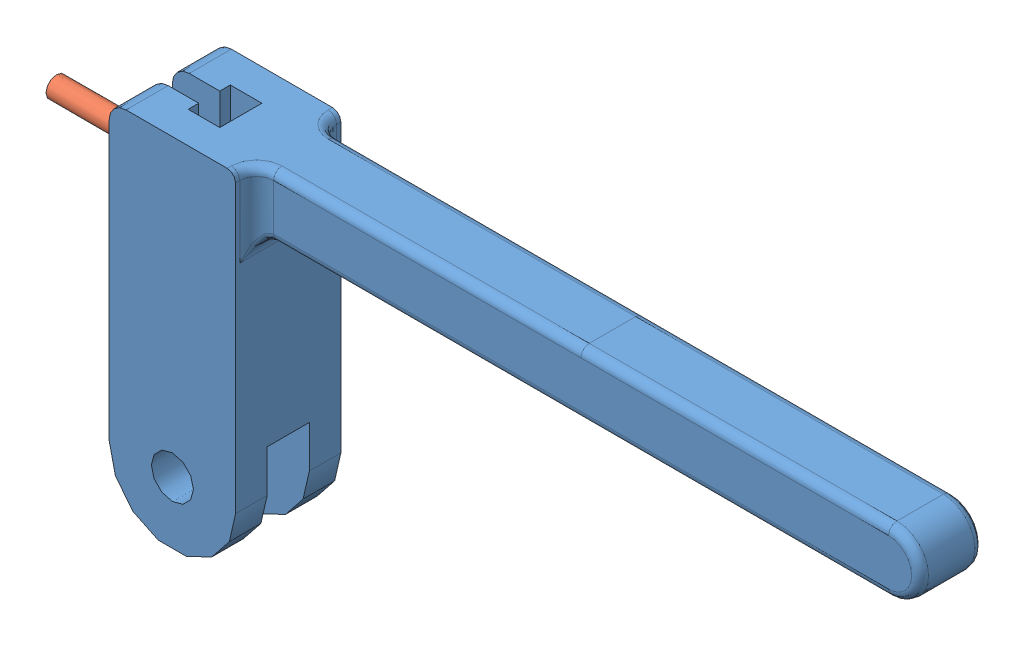
SolidWorks assembly Brake Lever Assembly 1-4, configuration Default. Lengths in mm.
Overall size (134.94 53.98 15.88).
2 component instances, 2 part files, 2 mates.
Components (placement in the parent):
- Brake Lever 1-4-1: Brake Lever 1-4 [Default] at origin size (119.06 53.98 15.88)
- Brake Cable Anchor & Cable 1-4-1: Brake Cable Anchor & Cable 1-4 [Default] at (0 34.29 0) size (27.78 4.76 6.35)
Mates (geometry in assembly coordinates):
- Concentric1: concentric anti-aligned: cylinder of Brake Lever 1-4-1 through (0 34.29 -3.175) axis (0 0 1) radius 2.3813; cylinder of Brake Cable Anchor & Cable 1-4-1 through (0 34.29 3.175) axis (0 0 -1) radius 2.3813
- Concentric2: concentric anti-aligned: cylinder of Brake Lever 1-4-1 through (0 34.29 0) axis (-1 0 0) radius 1.5875; cylinder of Brake Cable Anchor & Cable 1-4-1 through (-25.4 34.29 0) axis (1 0 0) radius 1.5875
